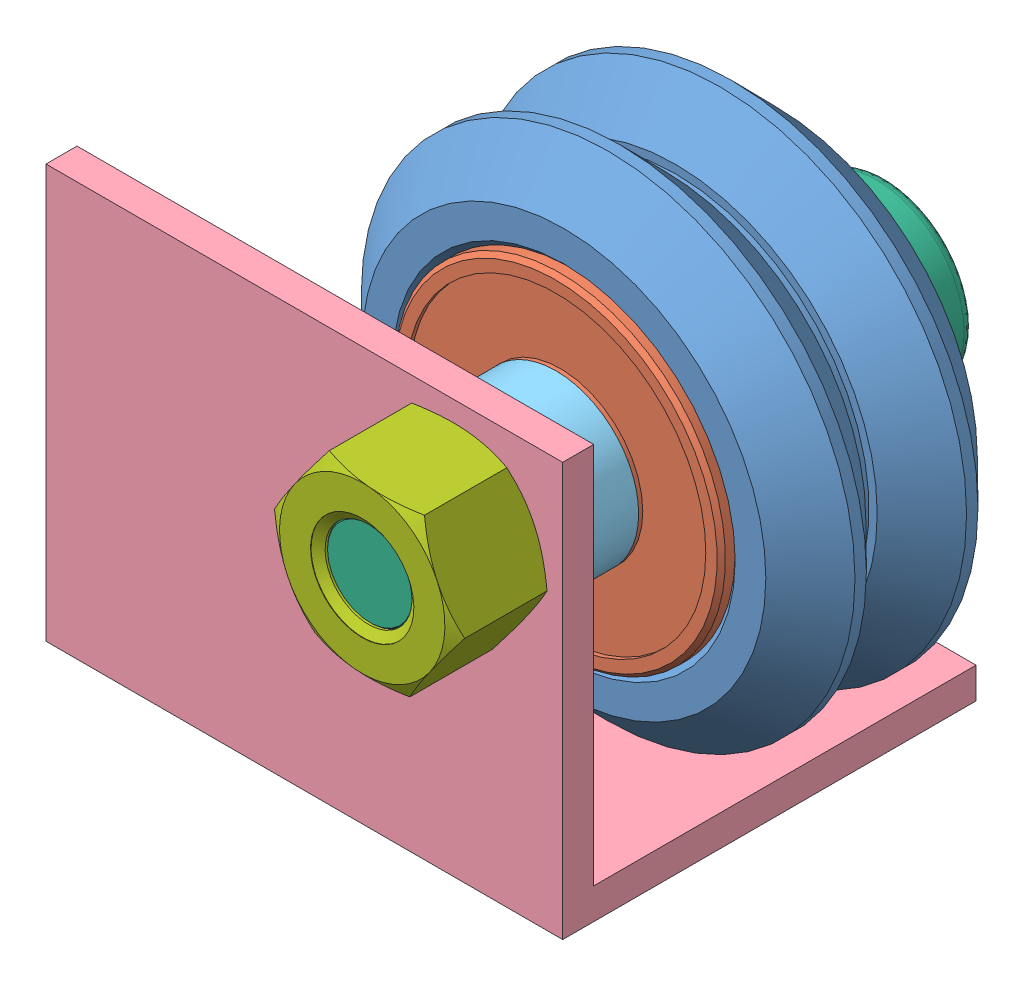
SolidWorks assembly stageCorner+Wheel, configuration Standard. Lengths in mm.
Overall size (34.45 33.8 25.38).
12 component instances, 9 part files, 11 mates.
Components (placement in the parent):
- Derlin-V-Wheel+Bearings-1: Derlin-V-Wheel+Bearings [Standard] at origin size (23.89 23.89 11)
  - Delrin Dual V-Wheel-1: Delrin Dual V-Wheel [Default] at origin size (23.89 23.89 10.23)
  - Precision Ball Bearing-1: Precision Ball Bearing [Default] at (0 0 3) x (0 0 -1) z (1 0 0) size (5 16 16)
  - Precision Ball Bearing-2: Precision Ball Bearing [Default] at (0 0 -3) x (0 0 -1) z (1 0 0) size (5 16 16)
  - 5mm Precision Washer-1: 5mm Precision Washer [Default] at (0 0 -0.5) x (0 0 1) z (-1 0 0) size (1 10 10)
- stageWheelAngle-1: stageWheelAngle [Standard] at (-20 -15 10.175) x (0 0 -1) z (1 0 0) size (20 20 25)
- .125 Inch Aluminum Spacer-1: .125 Inch Aluminum Spacer [Default] at (0 0 8.675) x (0 0 -1) z (1 0 0) size (3.17 8 8)
- socket head cap screw_din_a2-1: socket head cap screw_din_a2 [DIN 912 M5 x 20 --- 20C] at (0 0 -10.5) x (0 0 1) z (-1 0 0) size (25 8.5 8.5)
- hex nut style 1 gradeab_din_a2-1: hex nut style 1 gradeab_din_a2 [Hexagon Nut ISO 4032 - M5 - D - C] at (0 0 10.175) x (-0.906893 -0.42136 0) z (0 0 -1) size (8 9.24 4.7)
- 5mm x 8mm Bolt with Tee Nut-1: 5mm x 8mm Bolt with Tee Nut [Default] at (-25.4769 -46.5938 7.8945) x (0 -1 0) z (1 0 0) size (10.1 10 15)
  - 5mm x 8mm Low Profile Socket Head Screw-1: 5mm x 8mm Low Profile Socket Head Screw [5mm x 8mm Low Profile] at (-34.8438 7.7195 10.4769) size (10.1 9.5 9.5)
  - Tee nut-1: Tee nut [Default] at (-28.2938 2.7205 17.9769) x (0 0 -1) z (1 0 0) size (15 10 3.3)
Mates (geometry in assembly coordinates):
- Concentric1: concentric anti-aligned: cylinder of stageWheelAngle-1 through (0 0 10.175) axis (0 0 -1) radius 2.5; cylinder of .125 Inch Aluminum Spacer-1 through (0 0 5.5) axis (0 0 1) radius 2.65
- Coincident1: coincident anti-aligned: plane of stageWheelAngle-1 through (5 -15 8.675) normal (0 0 -1); plane of .125 Inch Aluminum Spacer-1 through (0 0 8.675) normal (0 0 1)
- Concentric2: concentric anti-aligned: cylinder of Derlin-V-Wheel+Bearings-1/Precision Ball Bearing-1 through (0 0 5.5) axis (0 0 -1) radius 2.5; cylinder of .125 Inch Aluminum Spacer-1 through (0 0 5.5) axis (0 0 1) radius 2.65
- Coincident2: coincident anti-aligned: plane of Derlin-V-Wheel+Bearings-1/Precision Ball Bearing-1 through (0 0 5.5) normal (0 0 1); plane of .125 Inch Aluminum Spacer-1 through (0 0 5.5) normal (0 0 -1)
- Concentric3: concentric anti-aligned: cone of Derlin-V-Wheel+Bearings-1/Precision Ball Bearing-2 through (0 0 -5.3) axis (0 0 1); cylinder of socket head cap screw_din_a2-1 through (0 0 -42.25) axis (0 0 -1) radius 4.25
- Coincident3: coincident anti-aligned: plane of Derlin-V-Wheel+Bearings-1/Precision Ball Bearing-2 through (0 0 -5.5) normal (0 0 -1); plane of socket head cap screw_din_a2-1 through (0 4.25 -5.5) normal (0 0 1)
- Concentric4: concentric aligned: cylinder of socket head cap screw_din_a2-1 through (0 0 -42.25) axis (0 0 -1) radius 2.5; cylinder of hex nut style 1 gradeab_din_a2-1 through (0 0 35.2125) axis (0 0 -1) radius 2.5
- Coincident4: coincident anti-aligned: plane of stageWheelAngle-1 through (5 -15 10.175) normal (0 0 1); plane of hex nut style 1 gradeab_din_a2-1 through (-1.9462 4.1888 10.175) normal (0 0 -1)
- Coincident5: coincident anti-aligned: plane of stageWheelAngle-1 through (5 -13.5 10.175) normal (0 1 0); plane of 5mm x 8mm Bolt with Tee Nut-1/5mm x 8mm Low Profile Socket Head Screw-1 through (-15 -13.5 -2.325) normal (0 -1 0)
- Concentric5: concentric anti-aligned: cylinder of stageWheelAngle-1 through (-15 5 0.175) axis (0 -1 0) radius 2.5; cylinder of 5mm x 8mm Bolt with Tee Nut-1/5mm x 8mm Low Profile Socket Head Screw-1 through (-15 -11.75 0.175) axis (0 1 0) radius 4.75
- Parallel1: parallel anti-aligned: plane of stageWheelAngle-1 through (5 -13.5 -9.825) normal (0 0 -1); plane of 5mm x 8mm Bolt with Tee Nut-1/Tee nut-1 through (-7.5 -19.95 5.174) normal (0 0 1)
